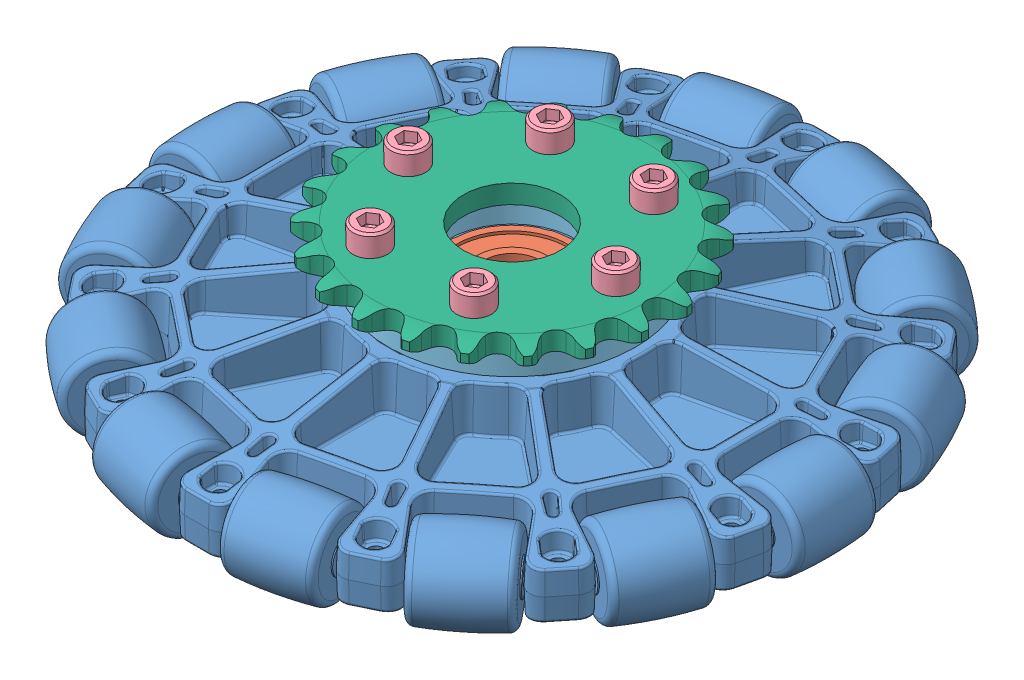
SolidWorks assembly omni_wheel_assm_geared sprocket, configuration Default. Lengths in mm.
Overall size (152.04 51.88 152.39).
13 component instances, 6 part files, 17 mates.
Components (placement in the parent):
- 6inch_omni-1: 6inch_omni [Default] at (-5.8198 16.297 -20.6554) size (152.04 25.4 152.39)
- plain 0500 bearing-1: plain 0500 bearing [Default] at (-5.8198 37.7283 -20.6554) x (1 0 0) z (0 1 0) size (28.57 28.57 7.94)
- flanged 0500 bearing-1: flanged 0500 bearing [Default] at (-5.8198 18.6783 -20.6554) x (0.923728 0 -0.383049) z (0 -1 0) size (31.75 31.75 7.94)
- Socket Head Cap Screw_AI-3: Socket Head Cap Screw_AI [HX-SHCS 0.19-32x1.75x1.75-C] at (-17.726 57.1498 -0.0332) x (0 -1 0) z (0.99911 0 -0.042182) size (49.28 7.94 7.94)
- Socket Head Cap Screw_AI-7: Socket Head Cap Screw_AI [HX-SHCS 0.19-32x1.75x1.75-C] at (-29.6323 57.1498 -20.6554) x (0 -1 0) z (0.536085 0 0.844164) size (49.28 7.94 7.94)
- Socket Head Cap Screw_AI-8: Socket Head Cap Screw_AI [HX-SHCS 0.19-32x1.75x1.75-C] at (-17.726 57.1498 -41.2777) x (0 -1 0) z (-0.463025 0 0.886345) size (49.28 7.94 7.94)
- Socket Head Cap Screw_AI-9: Socket Head Cap Screw_AI [HX-SHCS 0.19-32x1.75x1.75-C] at (6.0865 57.1498 -41.2777) x (0 -1 0) z (-0.99911 0 0.042182) size (49.28 7.94 7.94)
- Socket Head Cap Screw_AI-10: Socket Head Cap Screw_AI [HX-SHCS 0.19-32x1.75x1.75-C] at (17.9927 57.1498 -20.6554) x (0 -1 0) z (-0.536085 0 -0.844164) size (49.28 7.94 7.94)
- Socket Head Cap Screw_AI-11: Socket Head Cap Screw_AI [HX-SHCS 0.19-32x1.75x1.75-C] at (6.0865 57.1498 -0.0332) x (0 -1 0) z (0.463025 0 -0.886345) size (49.28 7.94 7.94)
- sprocket_spacer-1: sprocket_spacer [Default] at (-5.8198 13.122 -20.6554) x (-0.042182 0 -0.99911) z (0 1 0) size (57.15 57.15 6.35)
- sprocket_spacer_22t-1: sprocket_spacer_22t [Default] at (-5.8198 7.8087 -20.6554) x (0 -1 0) z (-0.886345 0 -0.463025) size (5.07 71.91 71.96)
- sprocket_spacer-2: sprocket_spacer [Default] at (-5.8198 44.872 -20.6554) x (0.866025 0 -0.5) z (0 -1 0) size (57.15 57.15 6.35)
- sprocket_spacer_22t-2: sprocket_spacer_22t [Default] at (-5.8198 50.1854 -20.6554) x (0 -1 0) z (0 0 1) size (5.07 71.91 71.96)
Mates (geometry in assembly coordinates):
- Concentric9: concentric anti-aligned: cylinder of 6inch_omni-1 through (-5.8198 34.077 -20.6554) axis (0 -1 0) radius 14.2812; cylinder of plain 0500 bearing-1 through (-5.8198 37.7283 -20.6554) axis (0 1 0) radius 14.2875
- Coincident8: coincident aligned: plane of 6inch_omni-1 through (-64.3668 41.697 -27.1324) normal (0 1 0); plane of plain 0500 bearing-1 through (-5.0809 41.697 -20.6554) normal (0 1 0)
- Concentric10: concentric anti-aligned: cylinder of 6inch_omni-1 through (-5.8198 23.917 -20.6554) axis (0 1 0) radius 14.2812; cylinder of flanged 0500 bearing-1 through (-5.8198 18.6783 -20.6554) axis (0 -1 0) radius 14.2875
- Coincident9: coincident anti-aligned: plane of 6inch_omni-1 through (-64.3668 16.297 -14.1784) normal (0 -1 0); plane of flanged 0500 bearing-1 through (-4.4867 16.297 -21.2083) normal (0 1 0)
- Concentric21: concentric aligned: cylinder of Socket Head Cap Screw_AI-3 through (-16.8455 90.973 0.4507) axis (0 1 0) radius 2.413; circle of sprocket_spacer-1
- Concentric23: concentric aligned: cylinder of Socket Head Cap Screw_AI-11 through (6.9458 90.973 -0.5538) axis (0 1 0) radius 2.413; circle of sprocket_spacer-1
- Coincident31: coincident anti-aligned: plane of 6inch_omni-1 through (-64.3668 16.297 -14.1784) normal (0 -1 0); plane of sprocket_spacer-1 through (-5.8198 16.297 -20.6554) normal (0 1 0)
- Concentric24: concentric anti-aligned: circle of Socket Head Cap Screw_AI-3; circle of sprocket_spacer_22t-1
- Concentric25: concentric anti-aligned: circle of Socket Head Cap Screw_AI-11; circle of sprocket_spacer_22t-1
- Coincident32: coincident anti-aligned: plane of sprocket_spacer-1 through (-7.0251 9.947 -49.205) normal (0 -1 0); plane of sprocket_spacer_22t-1 through (-13.0473 9.947 -6.8201) normal (0 1 0)
- Concentric26: concentric aligned: circle of plain 0500 bearing-1; circle of sprocket_spacer-2
- Coincident33: coincident anti-aligned: plane of 6inch_omni-1 through (-64.3668 41.697 -27.1324) normal (0 1 0); plane of sprocket_spacer-2 through (-5.8198 41.697 -20.6554) normal (0 -1 0)
- Concentric27: concentric anti-aligned: circle of Socket Head Cap Screw_AI-8; circle of sprocket_spacer-2
- Concentric28: concentric anti-aligned: cylinder of 6inch_omni-1 through (-17.726 -9.103 -41.2777) axis (0 -1 0) radius 2.5908; cylinder of Socket Head Cap Screw_AI-8 through (-17.726 90.973 -41.2777) axis (0 1 0) radius 2.413
- Concentric29: concentric anti-aligned: circle of 6inch_omni-1; circle of sprocket_spacer_22t-2
- Coincident34: coincident anti-aligned: plane of sprocket_spacer_22t-2 through (9.7897 48.047 -20.6554) normal (0 -1 0); plane of sprocket_spacer-2 through (18.9269 48.047 -34.9429) normal (0 1 0)
- Coincident35: coincident anti-aligned: plane of Socket Head Cap Screw_AI-8 through (-14.2083 52.3238 -39.44) normal (0 -1 0); plane of sprocket_spacer_22t-2 through (9.7897 52.3238 -20.6554) normal (0 1 0)
